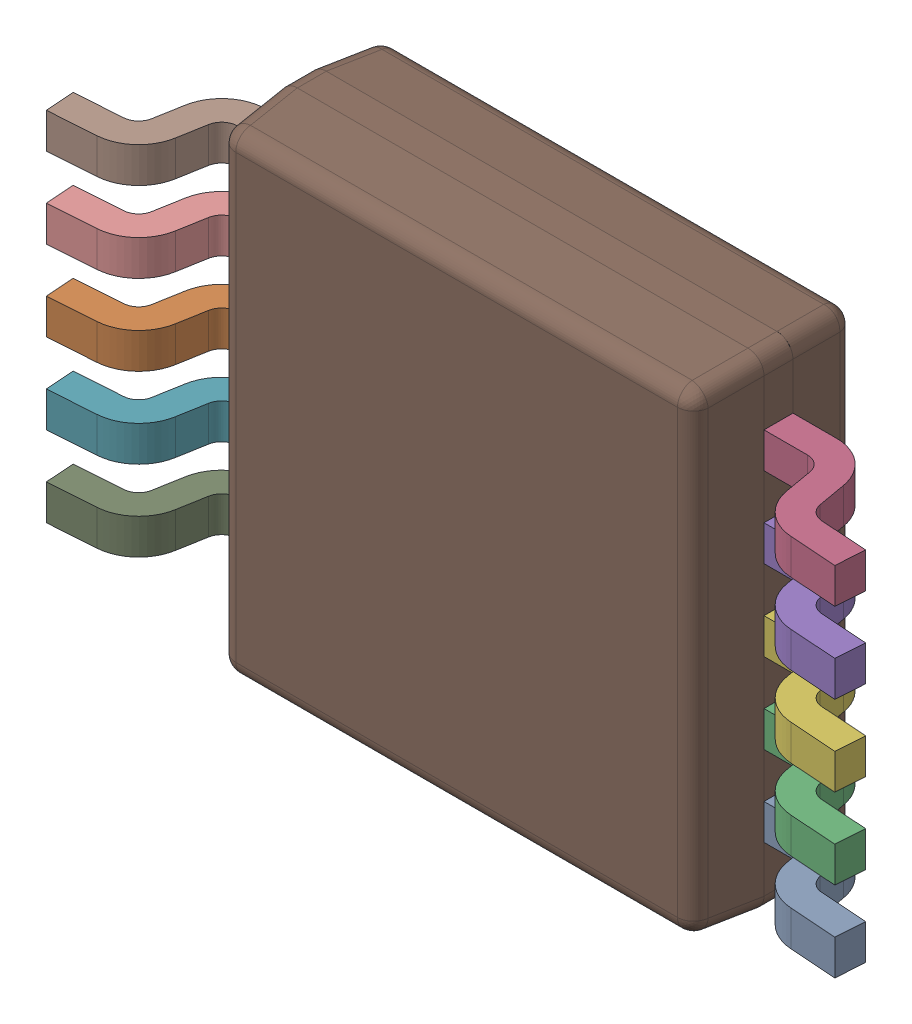
SolidWorks assembly IC3, configuration 默认. Lengths in mm.
Overall size (4.93 3 1.1).
12 component instances, 2 part files, 0 mates.
Components (placement in the parent):
- 6132016496-1: 6132016496 [默认] at (8.763 6.223 -2.3814) x (0 1 0) z (-1 0 0) size (3 1.1 4.93)
  - LEAD-SO-1: LEAD-SO [默认] at (-1 -0.44 -1.9) x (-1 0 0) z (0 0 -1) size (0.22 0.69 0.96)
  - LEAD-SO-2: LEAD-SO [默认] at (0 -0.44 1.9) size (0.22 0.69 0.96)
  - LEAD-SO-3: LEAD-SO [默认] at (-0.5 -0.44 -1.9) x (-1 0 0) z (0 0 -1) size (0.22 0.69 0.96)
  - LEAD-SO-4: LEAD-SO [默认] at (1 -0.44 -1.9) x (-1 0 0) z (0 0 -1) size (0.22 0.69 0.96)
  - LEAD-SO-5: LEAD-SO [默认] at (0.5 -0.44 -1.9) x (-1 0 0) z (0 0 -1) size (0.22 0.69 0.96)
  - LEAD-SO-6: LEAD-SO [默认] at (0 -0.44 -1.9) x (-1 0 0) z (0 0 -1) size (0.22 0.69 0.96)
  - LEAD-SO-7: LEAD-SO [默认] at (-0.5 -0.44 1.9) size (0.22 0.69 0.96)
  - LEAD-SO-8: LEAD-SO [默认] at (1 -0.44 1.9) size (0.22 0.69 0.96)
  - LEAD-SO-9: LEAD-SO [默认] at (-1 -0.44 1.9) size (0.22 0.69 0.96)
  - LEAD-SO-10: LEAD-SO [默认] at (0.5 -0.44 1.9) size (0.22 0.69 0.96)
  - BODY-SO-1: BODY-SO [默认] at origin size (3 1 3)
